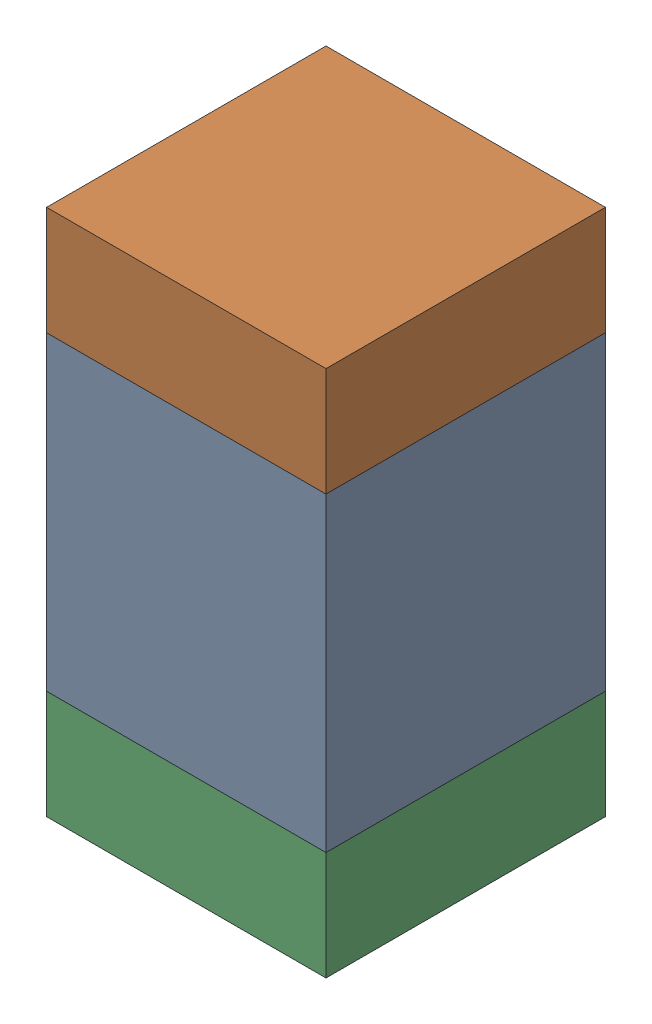
SolidWorks assembly C1, configuration Default. Lengths in mm.
Overall size (0.9 1.7 0.9).
6 component instances, 2 part files, 0 mates.
Components (placement in the parent):
- 5613956208-1: 5613956208 [Default] at (136.4 121.825 -2.5914) size (0.9 1 0.9)
  - Extruded_2-1: Extruded_2 [Default] at origin size (0.9 1 0.9)
- 5613953728-1: 5613953728 [Default] at (136.4 122.5 -2.5914) size (0.9 0.35 0.9)
  - Extruded_8-1: Extruded_8 [Default] at origin size (0.9 0.35 0.9)
- 5613953728-2: 5613953728 [Default] at (136.4 121.15 -2.5914) size (0.9 0.35 0.9)
  - Extruded_8-1: Extruded_8 [Default] at origin size (0.9 0.35 0.9)
